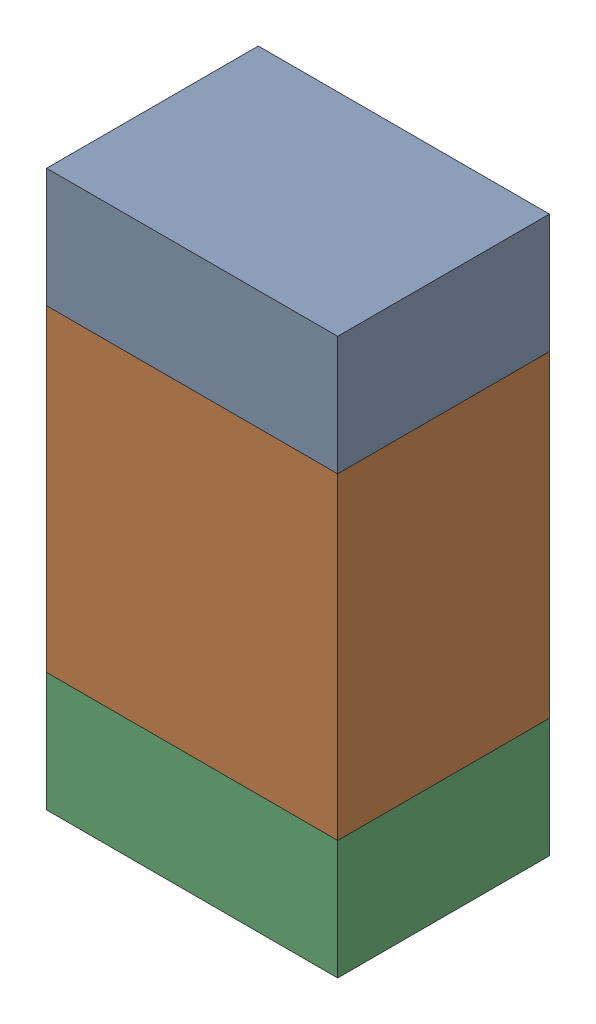
SolidWorks assembly R407PCB, configuration Default. Lengths in mm.
Overall size (0.55 1.05 0.4).
6 component instances, 2 part files, 0 mates.
Components (placement in the parent):
- 846483288-1: 846483288 [Default] at (83.3001 89.3124 0) size (0.55 0.22 0.4)
  - Extruded_12-1: Extruded_12 [Default] at origin size (0.55 0.22 0.4)
- 846483424-1: 846483424 [Default] at (83.3001 88.8999 0) size (0.55 0.6 0.4)
  - Extruded_13-1: Extruded_13 [Default] at origin size (0.55 0.6 0.4)
- 846483288-2: 846483288 [Default] at (83.3001 88.4874 0) size (0.55 0.22 0.4)
  - Extruded_12-1: Extruded_12 [Default] at origin size (0.55 0.22 0.4)
